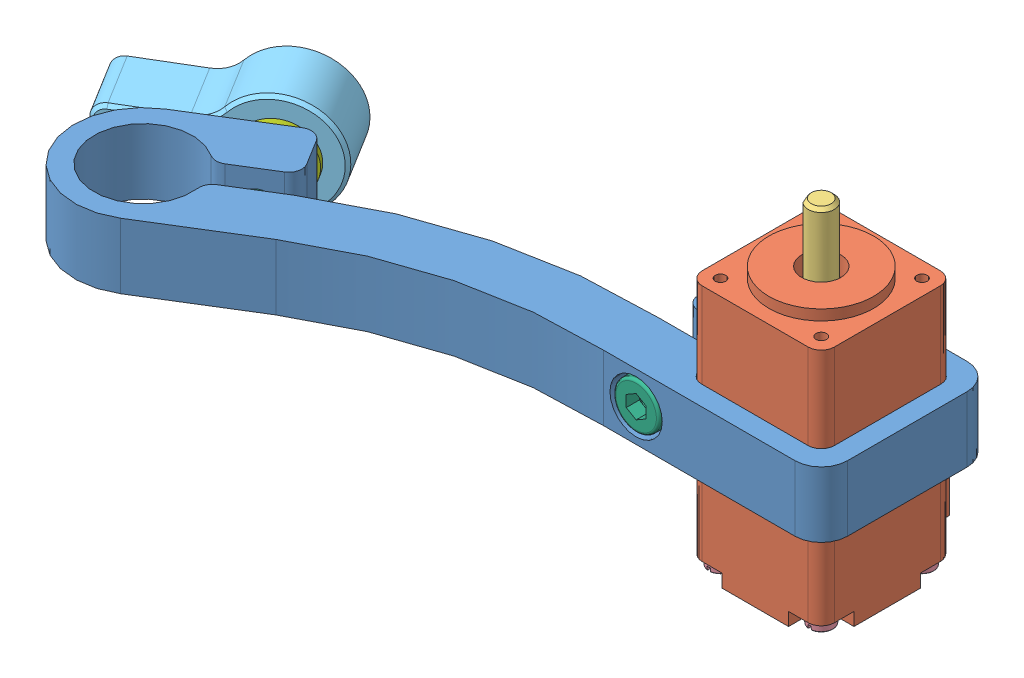
SolidWorks assembly holder_motor_screw, configuration По умолчанию. Lengths in mm.
Overall size (111.98 49.1 47.7).
13 component instances, 7 part files, 7 mates.
Components (placement in the parent):
- holder_motor_rod-1: holder_motor_rod [По умолчанию] at (-10.8807 20.7314 13.3285) size (103.65 10 47.3)
- Motor_NEMA8_Stepper-1: Motor_NEMA8_Stepper [По умолчанию] at (-19.6426 25.9326 24.2646) x (0 1 0) z (0 0 1) size (49.1 20.2 23.7)
  - Stator-1: Stator [По умолчанию] at (-20.6518 -8.7619 9.3639) size (40.1 20.2 23.7)
  - Rotor-1: Rotor [По умолчанию] at (-15.6518 1.3381 -0.7361) x (0 0.143607 -0.989635) z (1 0 0) size (4 4 44.1)
  - slotted cheese head screw_din-2: slotted cheese head screw_din [ISO 1207 - M2 x 20 --- 20N] at (-20.0518 9.0381 -8.4361) size (21.4 3.8 3.8)
  - slotted cheese head screw_din-3: slotted cheese head screw_din [ISO 1207 - M2 x 20 --- 20N] at (-20.0518 9.0381 6.9639) size (21.4 3.8 3.8)
  - slotted cheese head screw_din-4: slotted cheese head screw_din [ISO 1207 - M2 x 20 --- 20N] at (-20.0518 -6.3619 6.9639) size (21.4 3.8 3.8)
  - slotted cheese head screw_din-5: slotted cheese head screw_din [ISO 1207 - M2 x 20 --- 20N] at (-20.0518 -6.3619 -8.4361) size (21.4 3.8 3.8)
- flag_screw-1: flag_screw [По умолчанию] at (-69.1819 73.774 29.3373) x (0.009002 0.999944 -0.005557) z (-0.85088 0.010579 0.525254) size (16 29 29)
  - flag-1: flag [По умолчанию] at (-48.2962 13.0906 23.7085) size (16 10 29)
  - socket head cap screw_din-1: socket head cap screw_din [DIN 912 M4 x 25 --- 25N] at (-48.2962 23.0906 23.7085) x (0 -1 0) z (0 0 1) size (29 7 7)
  - plain washer 6902 type abc_din-1: plain washer 6902 type abc_din [DIN 6902-A4.55] at (-48.2962 13.0906 23.7085) x (0 -1 0) z (-0.000413 0 1) size (1 10 10)
- socket head cap screw_din-1: socket head cap screw_din [DIN 912 M4 x 16 --- 16N] at (-36.1807 25.7314 36.6285) x (0 0 -1) z (1 0 0) size (20 7 7)
Mates (geometry in assembly coordinates):
- Параллельность1: parallel aligned: plane of holder_motor_rod-1 through (-44.0741 30.7314 106.5964) normal (0 1 0); plane of Motor_NEMA8_Stepper-1/Stator-1 through (-10.8807 43.7808 33.6285) normal (0 1 0)
- Совпадение1: coincident anti-aligned: plane of holder_motor_rod-1 through (-10.8807 30.7314 13.3285) normal (-1 0 0); plane of Motor_NEMA8_Stepper-1/Stator-1 through (-10.8807 43.7808 33.6285) normal (1 0 0)
- Совпадение2: coincident anti-aligned: plane of holder_motor_rod-1 through (-10.8807 30.7314 33.6285) normal (0 0 -1); plane of Motor_NEMA8_Stepper-1/Stator-1 through (-10.8807 43.7808 33.6285) normal (0 0 1)
- Концентричный1: concentric aligned: cylinder of holder_motor_rod-1 through (-89.5746 25.7314 42.407) axis (-0.525284 0 -0.850927) radius 1.65; cylinder of flag_screw-1/socket head cap screw_din-1 through (-118.5966 25.7314 -4.6067) axis (-0.525284 0 -0.850927) radius 2
- Совпадение3: coincident anti-aligned: plane of holder_motor_rod-1 through (-106.5462 30.7314 38.1938) normal (-0.525284 0 -0.850927); plane of flag_screw-1/plain washer 6902 type abc_din-1 through (-96.1407 25.7314 31.7704) normal (0.525284 0 0.850927)
- Концентричный2: concentric aligned: cylinder of holder_motor_rod-1 through (-36.1807 25.7314 36.6285) axis (0 0 1) radius 2.25; cylinder of socket head cap screw_din-1 through (-36.1807 25.7314 68.3785) axis (0 0 1) radius 2
- Совпадение4: coincident anti-aligned: plane of holder_motor_rod-1 through (-33.9307 25.7314 32.6285) normal (0 0 1); plane of socket head cap screw_din-1 through (-36.1807 29.2314 32.6285) normal (0 0 -1)
